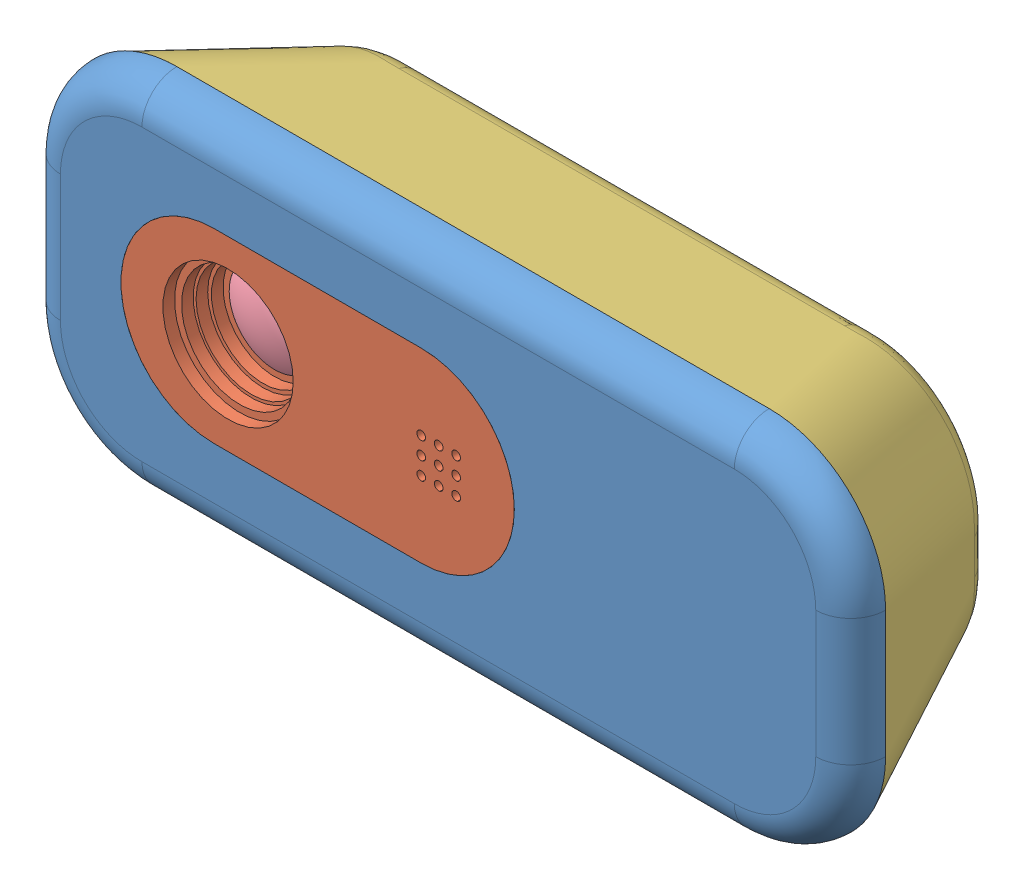
SolidWorks assembly webcam, configuration Default. Lengths in mm.
Overall size (70.96 31.91 23.6).
5 component instances, 5 part files, 10 mates.
Components (placement in the parent):
- Front-1: Front [Default] at origin size (70.9 30.9 3)
- camera_1-1: camera_1 [Default] at (-10.35 0 -3.5) size (33.8 16 5)
- housing-1: housing [Default] at (0 0 -1.5) x (-1 0 0) z (0 0 -1) size (70.96 31.91 20.65)
- lens-1: lens [Default] at (-18.05 0 -2) x (0 0 1) z (-1 0 0) size (1 7.8 7.8)
- camera_2-1: camera_2 [Default] at (-18.05 0 -3.4) x (0.927559 0.373676 0) z (0 0 1) size (7.8 7.8 0.9)
Mates (geometry in assembly coordinates):
- Coincident1: coincident anti-aligned: plane of Front-1 through (-19.25 8 -1.5) normal (0 -1 0); plane of camera_1-1 through (-19.25 8 1.5) normal (0 1 0)
- Concentric1: concentric anti-aligned: cylinder of Front-1 through (-1.45 0 -1.5) axis (0 0 1) radius 8; cylinder of camera_1-1 through (-1.45 0 1.5) axis (0 0 -1) radius 8
- Coincident2: coincident aligned: plane of Front-1 through (-25.45 -5.45 1.5) normal (0 0 1); plane of camera_1-1 through (-19.25 0 1.5) normal (0 0 1)
- Coincident3: coincident anti-aligned: plane of Front-1 through (-25.45 -5.45 -1.5) normal (0 0 -1); plane of housing-1 through (25.45 -5.45 -1.5) normal (0 0 1)
- Coincident4: coincident anti-aligned: line of Front-1 through (25.45 15.45 -1.5) axis (-1 0 0); line of housing-1 through (-25.45 15.45 -1.5) axis (1 0 0)
- Coincident5: coincident anti-aligned: line of Front-1 through (-35.45 5.45 -1.5) axis (0 -1 0); line of housing-1 through (-35.45 -5.45 -1.5) axis (0 1 0)
- Coincident19: coincident anti-aligned: cylinder of camera_1-1 through (-18.05 0 -3.5) axis (0 0 1) radius 3.9; circle of lens-1
- Coincident20: coincident aligned: circle of camera_1-1; circle of lens-1
- Concentric11: concentric anti-aligned: cylinder of camera_1-1 through (-18.05 0 -3.5) axis (0 0 1) radius 3.9; cylinder of camera_2-1 through (-18.05 0 -2.5) axis (0 0 -1) radius 3.9
- Coincident21: coincident anti-aligned: plane of lens-1 through (-18.05 0 -2.5) normal (0 0 -1); plane of camera_2-1 through (-18.05 0 -2.5) normal (0 0 1)
